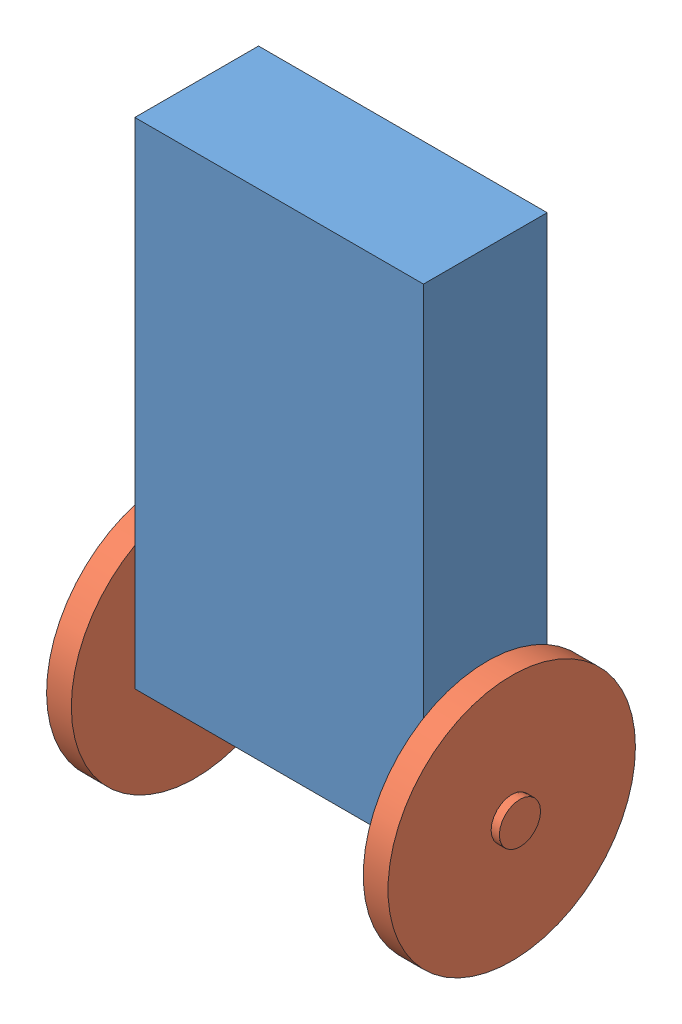
SolidWorks assembly wahadlo, configuration Domyślna. Lengths in mm.
Overall size (434 778.41 391.82).
3 component instances, 2 part files, 4 mates.
Components (placement in the parent):
- korpus-1: korpus [Domyślna] at (-65.0928 -33.3852 -7.5) size (360 600 150)
- kolo-1: kolo [Domyślna] at (286.9072 -15.8852 67.5) x (0 -1 0) z (0 0 1) size (300 40 300)
- kolo-2: kolo [Domyślna] at (-67.0928 -15.8852 67.5) x (0 -0.381849 0.924225) z (0 -0.924225 -0.381849) size (300 40 300)
Mates (geometry in assembly coordinates):
- Koncentryczne1: concentric aligned: cylinder of korpus-1 through (-70.0928 -15.8852 67.5) axis (1 0 0) radius 17.5; cylinder of kolo-2 through (-70.0928 -15.8852 67.5) axis (1 0 0) radius 17.5
- Wspólnie3: coincident anti-aligned: plane of korpus-1 through (-70.0928 -15.8852 67.5) normal (-1 0 0); plane of kolo-2 through (-70.0928 -15.8852 67.5) normal (1 0 0)
- Wspólnie4: coincident anti-aligned: plane of korpus-1 through (289.9072 -15.8852 67.5) normal (1 0 0); plane of kolo-1 through (289.9072 -15.8852 67.5) normal (-1 0 0)
- Koncentryczne2: concentric aligned: cylinder of korpus-1 through (289.9072 -15.8852 67.5) axis (-1 0 0) radius 17.5; cylinder of kolo-1 through (289.9072 -15.8852 67.5) axis (-1 0 0) radius 17.5
